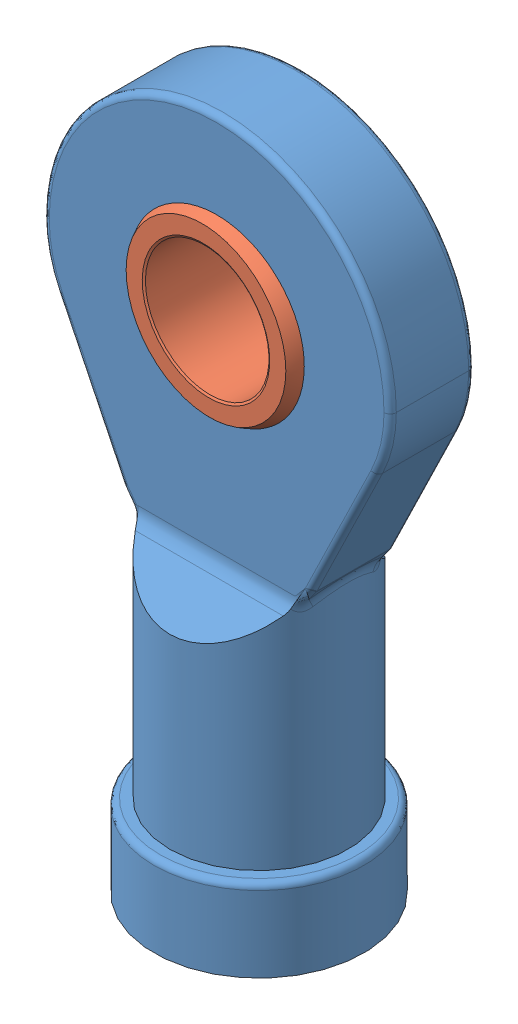
SolidWorks assembly igubal_SphericalRodEnd, configuration Default. Lengths in mm.
Overall size (43 106 25.98).
2 component instances, 2 part files, 1 mates.
Components (placement in the parent):
- igubal_SphericalRodEnd_RodEnd-1: igubal_SphericalRodEnd_RodEnd [Default] at (36.3685 5.5292 61.283) size (43 96 25.98)
- igubal_SphericalRodEnd_Ball-1: igubal_SphericalRodEnd_Ball [Default] at (36.3685 70.0299 61.283) x (0.858634 -0.511963 0.02535) z (-0.035096 -0.009379 0.99934) size (24.13 24.13 12.7)
Mates (geometry in assembly coordinates):
- Concentric1: concentric: sphere of igubal_SphericalRodEnd_RodEnd-1; sphere of igubal_SphericalRodEnd_Ball-1
